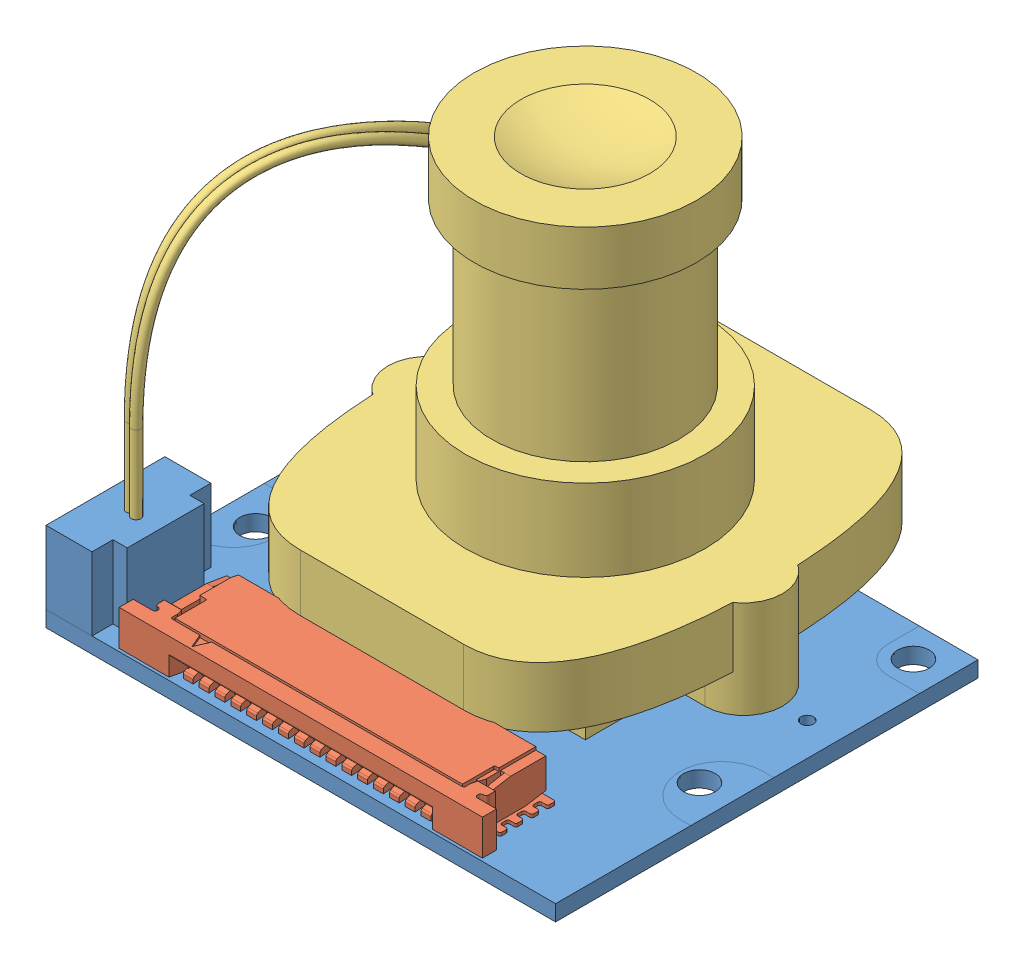
SolidWorks assembly Raspberry Pi Camera, configuration Default. Lengths in mm.
Overall size (32.15 27.14 30.78).
5 component instances, 4 part files, 11 mates.
Components (placement in the parent):
- camera pcb-1: camera pcb [Default] at origin size (32.15 5.6 26.65)
- TE-1-84952-5-1: TE-1-84952-5 [Default] at (0 2.315 16.92) size (22.92 2.56 6.54)
- camera lens-1: camera lens [Default] at (0 1 0) size (27.15 24.9 27.93)
- 92005A002_METRIC PAN HEAD PHILLIPS MACHINE SCREW-1: 92005A002_METRIC PAN HEAD PHILLIPS MACHINE SCREW [92005A002] at (10 3 0) x (1 0 0) z (0 -1 0) size (3.2 3.2 4.3)
- 92005A002_METRIC PAN HEAD PHILLIPS MACHINE SCREW-2: 92005A002_METRIC PAN HEAD PHILLIPS MACHINE SCREW [92005A002] at (-10 3 0) x (0.982082 0 -0.188455) z (0 -1 0) size (3.2 3.2 4.3)
Mates (geometry in assembly coordinates):
- Coincident1: coordinate: point of camera pcb-1; point of assembly
- Coincident2: coincident aligned: plane of camera pcb-1 through (-16.075 1 17.95) normal (0 0 1); plane of TE-1-84952-5-1 through (8.09 3.42 17.95) normal (0 0 1)
- Coincident3: coincident anti-aligned: plane of camera pcb-1 through (0 1 0) normal (0 1 0); plane of TE-1-84952-5-1 through (0 1 16.92) normal (0 -1 0)
- Width1: width anti-aligned: plane of camera pcb-1 through (-16.075 1 17.95) normal (-1 0 0); plane of TE-1-84952-5-1 through (16.075 1 17.95) normal (1 0 0); plane of camera pcb-1 through (11.46 3.42 17.95) normal (1 0 0); plane of TE-1-84952-5-1 through (-11.46 3.42 17.06) normal (-1 0 0)
- Concentric1: concentric aligned: cylinder of camera pcb-1 through (10 1 0) axis (0 -1 0) radius 1; cylinder of camera lens-1 through (10 3.35 0) axis (0 -1 0) radius 0.8
- Concentric2: concentric aligned: cylinder of camera pcb-1 through (-10 1 0) axis (0 -1 0) radius 1; cylinder of camera lens-1 through (-10 3.35 0) axis (0 -1 0) radius 0.8
- Coincident4: coincident anti-aligned: plane of camera pcb-1 through (0 1 0) normal (0 1 0); plane of camera lens-1 through (0 1 0) normal (0 -1 0)
- Coincident5: coincident anti-aligned: plane of camera pcb-1 through (0 0 0) normal (0 -1 0); plane of 92005A002_METRIC PAN HEAD PHILLIPS MACHINE SCREW-1 through (10 0 0) normal (0 1 0)
- Concentric3: concentric aligned: cylinder of camera lens-1 through (10 3.35 0) axis (0 -1 0) radius 0.8; cylinder of 92005A002_METRIC PAN HEAD PHILLIPS MACHINE SCREW-1 through (10 3 0) axis (0 -1 0) radius 0.5727
- Coincident6: coincident anti-aligned: plane of camera pcb-1 through (0 0 0) normal (0 -1 0); plane of 92005A002_METRIC PAN HEAD PHILLIPS MACHINE SCREW-2 through (-10 0 0) normal (0 1 0)
- Concentric4: concentric aligned: cylinder of camera lens-1 through (-10 3.35 0) axis (0 -1 0) radius 0.8; cylinder of 92005A002_METRIC PAN HEAD PHILLIPS MACHINE SCREW-2 through (-10 3 0) axis (0 -1 0) radius 0.5727
